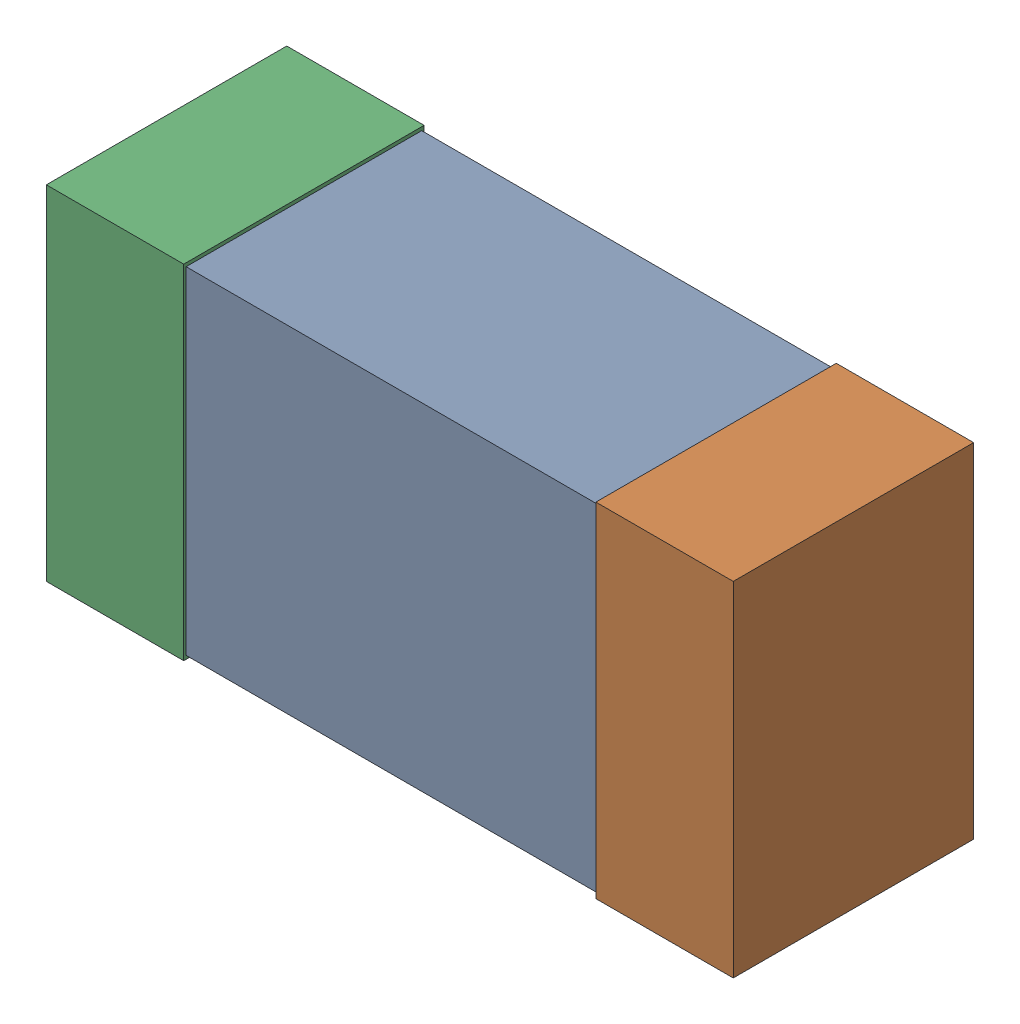
SolidWorks assembly 6074689360, configuration Predeterminado. Lengths in mm.
Overall size (1 0.5 0.35).
3 component instances, 3 part files, 0 mates.
Components (placement in the parent):
- body-1-1: body-1 [Predeterminado] at (-0.3 -0.245 0.0035) size (0.6 0.49 0.34)
- term2-1: term2 [Predeterminado] at (0.3 -0.25 0) size (0.2 0.5 0.35)
- term1-1: term1 [Predeterminado] at (-0.5 -0.25 0) size (0.2 0.5 0.35)
